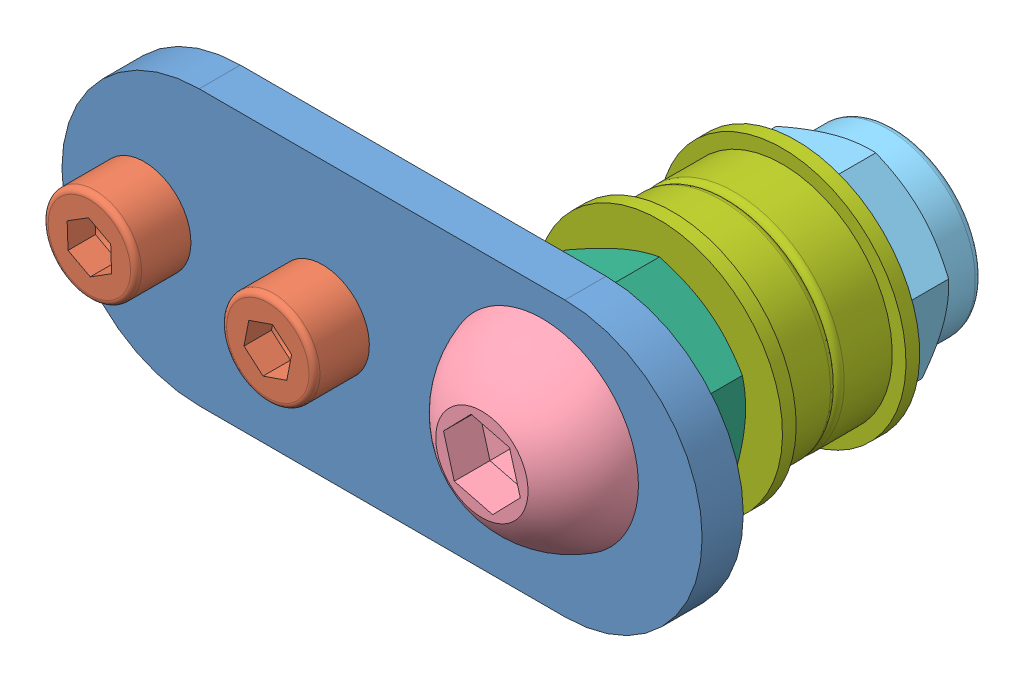
SolidWorks assembly ASM X-Belt Tensioner, configuration Standard. Lengths in mm.
Overall size (52.96 35.92 30.9).
11 component instances, 7 part files, 17 mates.
Components (placement in the parent):
- X Adjustment Block-1: X Adjustment Block [Standard] at (0 0 123.55) x (0 0 1) z (0 1 0) size (3 46.65 20)
- M4X8 Socket Head Screw-1: M4X8 Socket Head Screw [Standard] at (119.0857 138 0) x (0 0 -1) z (0.999363 0.035694 0) size (12 6.8 6.8)
- M5 T-Slot Nut-1: M5 T-Slot Nut [Standard] at (119.0857 138 -5.6373) x (-1 0 0) z (0 0 -1) size (6 9.5 4.1)
- M5 T-Slot Nut-2: M5 T-Slot Nut [Standard] at (132.0857 138 -5.6373) x (-1 0 0) z (0 0 -1) size (6 9.5 4.1)
- M4X8 Socket Head Screw-2: M4X8 Socket Head Screw [Standard] at (132.0857 138 0) x (0 0 -1) z (0.326012 -0.945366 0) size (12 6.8 6.8)
- ASM X-Roller Bolt-1: ASM X-Roller Bolt [Standard] at (148.0857 139 4.4) x (0 0 -1) z (0.697352 0.716729 0) size (30.9 25.4 25.4)
  - M8X25 Pan Head Screw-1: M8X25 Pan Head Screw [Standard] at origin size (30.62 14.79 14.79)
  - M8 Self-locking nut-1: M8 Self-locking nut [Standard] at (27.7325 0 0) x (0 0.488663 0.872473) z (1 0 0) size (15.01 13 7.18)
  - M8 nut-1: M8 nut [Standard] at (7.4 0 0) x (0 0.613039 0.790053) z (-1 0 0) size (15.01 13 5.5)
  - F688 pillow-1: F688 pillow [Standard] at (22.9 0 0) x (0 0.424513 0.905422) z (0 -0.905422 0.424513) size (18 5 18)
  - F688 pillow-2: F688 pillow [Standard] at (12.9 0 0) x (0 0.751639 -0.659574) z (0 -0.659574 -0.751639) size (18 5 18)
Mates (geometry in assembly coordinates):
- Konzentrisch29: concentric aligned: cylinder of M4X8 Socket Head Screw-1 through (119.0857 138 0.9416) axis (0 0 1) radius 2; cylinder of M5 T-Slot Nut-1 through (119.0857 138 -8.5663) axis (0 0 1) radius 2.5
- Deckungsgleich27: coincident anti-aligned: plane of M4X8 Socket Head Screw-1 through (118.9644 141.3978 0) normal (0 0 -1); plane of X Adjustment Block-1 through (168.0857 139 0) normal (0 0 1)
- Konzentrisch30: concentric anti-aligned: cylinder of X Adjustment Block-1 through (132.0857 138 -5) axis (0 0 -1) radius 2.1; cylinder of M5 T-Slot Nut-2 through (132.0857 138 -8.5663) axis (0 0 1) radius 2.5
- Konzentrisch31: concentric anti-aligned: cylinder of X Adjustment Block-1 through (119.0857 138 -5) axis (0 0 -1) radius 2.1; cylinder of M5 T-Slot Nut-1 through (119.0857 138 -8.5663) axis (0 0 1) radius 2.5
- Konzentrisch33: concentric anti-aligned: cylinder of X Adjustment Block-1 through (132.0857 138 -5) axis (0 0 -1) radius 2.1; cylinder of M4X8 Socket Head Screw-2 through (132.0857 138 0.9416) axis (0 0 1) radius 2
- Deckungsgleich29: coincident anti-aligned: plane of X Adjustment Block-1 through (168.0857 139 0) normal (0 0 1); plane of M4X8 Socket Head Screw-2 through (135.3 139.1084 0) normal (0 0 -1)
- Konzentrisch71: concentric anti-aligned: cylinder of X Adjustment Block-1 through (148.0857 139 -5) axis (0 0 -1) radius 4.1; cylinder of ASM X-Roller Bolt-1/M8X25 Pan Head Screw-1 through (148.0857 139 -10) axis (0 0 1) radius 4
- Deckungsgleich64: coincident anti-aligned: plane of X Adjustment Block-1 through (168.0857 139 0) normal (0 0 1); plane of ASM X-Roller Bolt-1/M8X25 Pan Head Screw-1 through (148.0857 139 0) normal (0 0 -1)
- Deckungsgleich65: coincident anti-aligned: plane of X Adjustment Block-1 through (168.0857 139 -3) normal (0 0 -1); plane of ASM X-Roller Bolt-1/M8 nut-1 through (161.0046 137.5497 -3) normal (0 0 1)
- Parallel1: parallel aligned: plane of X Adjustment Block-1 through (195.9044 128 0) normal (0 -1 0); plane of M5 T-Slot Nut-2 through (129.0857 133.25 -6.3) normal (0 -1 0)
- Parallel2: parallel aligned: plane of M5 T-Slot Nut-1 through (122.0857 138 -5.6373) normal (1 0 0); plane of M5 T-Slot Nut-2 through (135.0857 138 -5.6373) normal (1 0 0)
- Deckungsgleich66: coincident aligned: plane of M5 T-Slot Nut-1 through (116.0857 133.25 -4.8) normal (0 0 1); plane of M5 T-Slot Nut-2 through (129.0857 133.25 -4.8) normal (0 0 1)
- Abstand1: distance = 1.8 mm anti-aligned: plane of M5 T-Slot Nut-2 through (129.0857 133.25 -4.8) normal (0 0 1); plane of X Adjustment Block-1 through (168.0857 139 -3) normal (0 0 -1)
- Deckungsgleich67: coincident aligned: plane of X Adjustment Block-1 through (168.0857 139 0) normal (0 0 1); plane of assembly through (0 0 0) normal (0 0 1)
- Deckungsgleich68: coincident: plane of assembly through (0 0 0) normal (0 0 1); plane of X Adjustment Block-1 through (0 0 123.55) normal (0 0 1); plane of assembly
- Deckungsgleich69: coincident aligned: plane of X Adjustment Block-1 through (0 0 123.55) normal (0 1 0); plane of assembly through (0 0 0) normal (0 1 0)
- Deckungsgleich70: coincident aligned: plane of X Adjustment Block-1 through (0 0 123.55) normal (1 0 0); plane of assembly through (0 0 0) normal (1 0 0)
